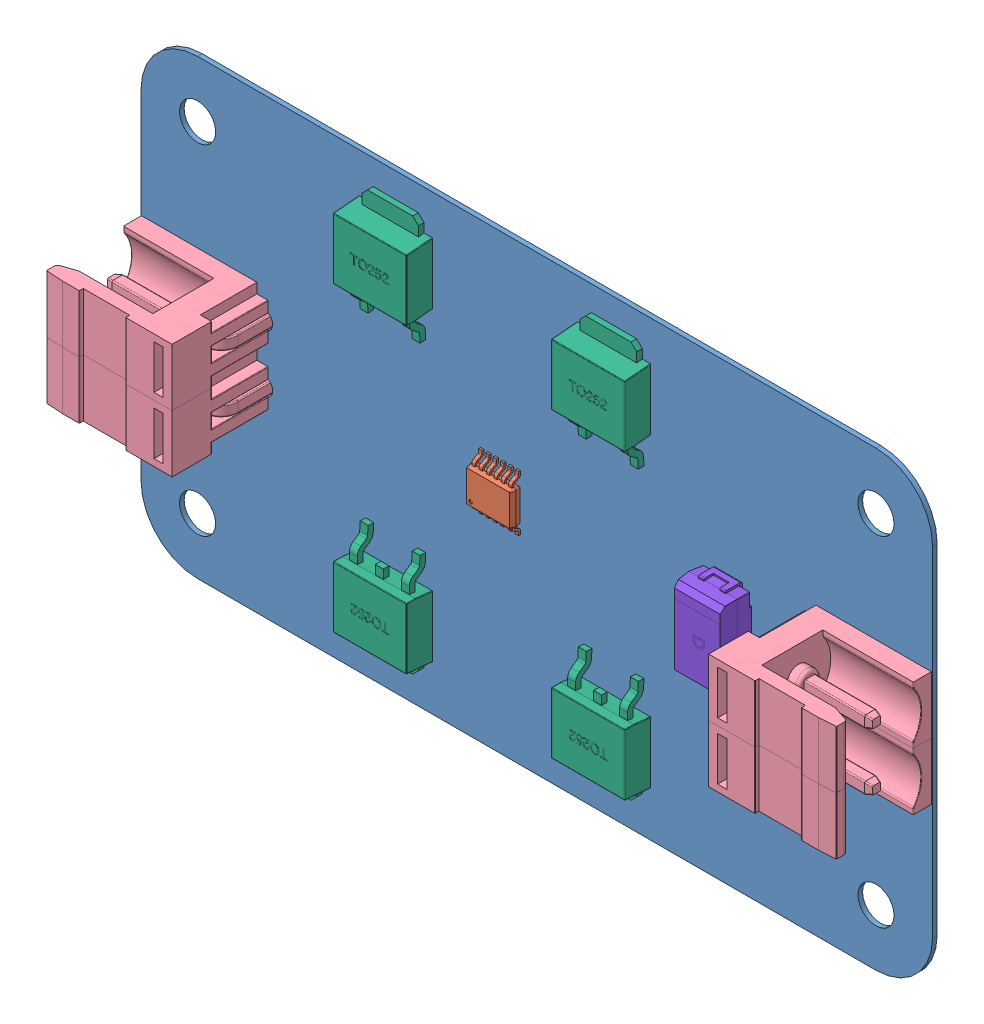
SolidWorks assembly 理想整流桥, configuration 默认. Lengths in mm.
Overall size (70 40 11.5).
38 component instances, 8 part files, 0 mates.
Components (placement in the parent):
- Board-1: Board [默认] at origin size (70 40 0.41)
  - Open CASCADE STEP translator 6.8 4.1.1-1: Open CASCADE STEP translator 6.8 4.1.1 [默认] at (0 0 -0.4115) size (70 40 0.41)
- Open CASCADE STEP translator 6.8 4.2-1: Open CASCADE STEP translator 6.8 4.2 [默认] at origin size (4.04 4.9 1.1)
  - User_Library-msop-12-1: User_Library-msop-12 [默认] at (67.1831 53.7211 0) x (0 1 0) z (0 0 1) size (4.9 4.04 1.1)
- P2-1: P2 [默认] at origin size (11.3 10.16 11.5)
  - KF2EDGK-1P_H-1: KF2EDGK-1P_H [默认] at (94.488 56.388 0) x (0 1 0) z (0 0 1) size (5.08 11.3 11.5)
    - LOGO横_-_0.5MM-1: LOGO横_-_0.5MM [默认] at (0.513 -1.4708 0) x (-1 0 0) z (0 0 -1) size (1.35 0.5 0.02)
    - KF2EDGK-1P_H-1: KF2EDGK-1P_H [默认] at origin size (5.08 11.3 11.5)
  - KF2EDGK-1P_H-2: KF2EDGK-1P_H [默认] at (94.4881 51.3079 0) x (0 1 0) z (0 0 1) size (5.08 11.3 11.5)
    - LOGO横_-_0.5MM-1: LOGO横_-_0.5MM [默认] at (0.513 -1.4708 0) x (-1 0 0) z (0 0 -1) size (1.35 0.5 0.02)
    - KF2EDGK-1P_H-1: KF2EDGK-1P_H [默认] at origin size (5.08 11.3 11.5)
- P1-1: P1 [默认] at origin size (11.3 10.16 11.5)
  - KF2EDGK-1P_H-1: KF2EDGK-1P_H [默认] at (46.228 51.308 0) x (0 -1 0) z (0 0 1) size (5.08 11.3 11.5)
    - LOGO横_-_0.5MM-1: LOGO横_-_0.5MM [默认] at (0.513 -1.4708 0) x (-1 0 0) z (0 0 -1) size (1.35 0.5 0.02)
    - KF2EDGK-1P_H-1: KF2EDGK-1P_H [默认] at origin size (5.08 11.3 11.5)
  - KF2EDGK-1P_H-2: KF2EDGK-1P_H [默认] at (46.2279 56.3881 0) x (0 -1 0) z (0 0 1) size (5.08 11.3 11.5)
    - LOGO横_-_0.5MM-1: LOGO横_-_0.5MM [默认] at (0.513 -1.4708 0) x (-1 0 0) z (0 0 -1) size (1.35 0.5 0.02)
    - KF2EDGK-1P_H-1: KF2EDGK-1P_H [默认] at origin size (5.08 11.3 11.5)
- MTG2-1: MTG2 [默认] at origin size (6.5 9.42 2.31)
  - TO252-1: TO252 [默认] at (55.612 61.9891 0) size (6.5 9.42 2.31)
    - LOGO_-1: LOGO_ [默认] at (2.3503 3.4211 -0.0025) x (-1 0 0) z (0 0 -1) size (0.75 0.87 0.01)
    - TO252-1: TO252 [默认] at origin size (6.5 9.42 2.3)
- MTG1-1: MTG1 [默认] at origin size (6.5 9.42 2.31)
  - TO252-1: TO252 [默认] at (74.916 61.9891 0) size (6.5 9.42 2.31)
    - LOGO_-1: LOGO_ [默认] at (2.3503 3.4211 -0.0025) x (-1 0 0) z (0 0 -1) size (0.75 0.87 0.01)
    - TO252-1: TO252 [默认] at origin size (6.5 9.42 2.3)
- MBG2-1: MBG2 [默认] at origin size (6.5 9.42 2.31)
  - TO252-1: TO252 [默认] at (60.212 45.7069 0) x (-1 0 0) z (0 0 1) size (6.5 9.42 2.31)
    - LOGO_-1: LOGO_ [默认] at (2.3503 3.4211 -0.0025) x (-1 0 0) z (0 0 -1) size (0.75 0.87 0.01)
    - TO252-1: TO252 [默认] at origin size (6.5 9.42 2.3)
- MBG1-1: MBG1 [默认] at origin size (6.5 9.42 2.31)
  - TO252-1: TO252 [默认] at (79.516 45.7069 0) x (-1 0 0) z (0 0 1) size (6.5 9.42 2.31)
    - LOGO_-1: LOGO_ [默认] at (2.3503 3.4211 -0.0025) x (-1 0 0) z (0 0 -1) size (0.75 0.87 0.01)
    - TO252-1: TO252 [默认] at origin size (6.5 9.42 2.3)
- E1-1: E1 [默认] at origin size (4.3 7.3 2.85)
  - CD_D(7343H)-1: CD_D(7343H) [默认] at (87.376 53.848 0) x (0 -1 0) z (0 0 1) size (7.3 4.3 2.85)
    - LOGO__2-1: LOGO__2 [默认] at (0 0.0355 -0.005) x (-1 0 0) z (0 0 -1) size (1.5 1.73 0.01)
    - CD_D(7343)-1: CD_D(7343) [默认] at (0 0 1.4) size (7.3 4.3 2.84)
